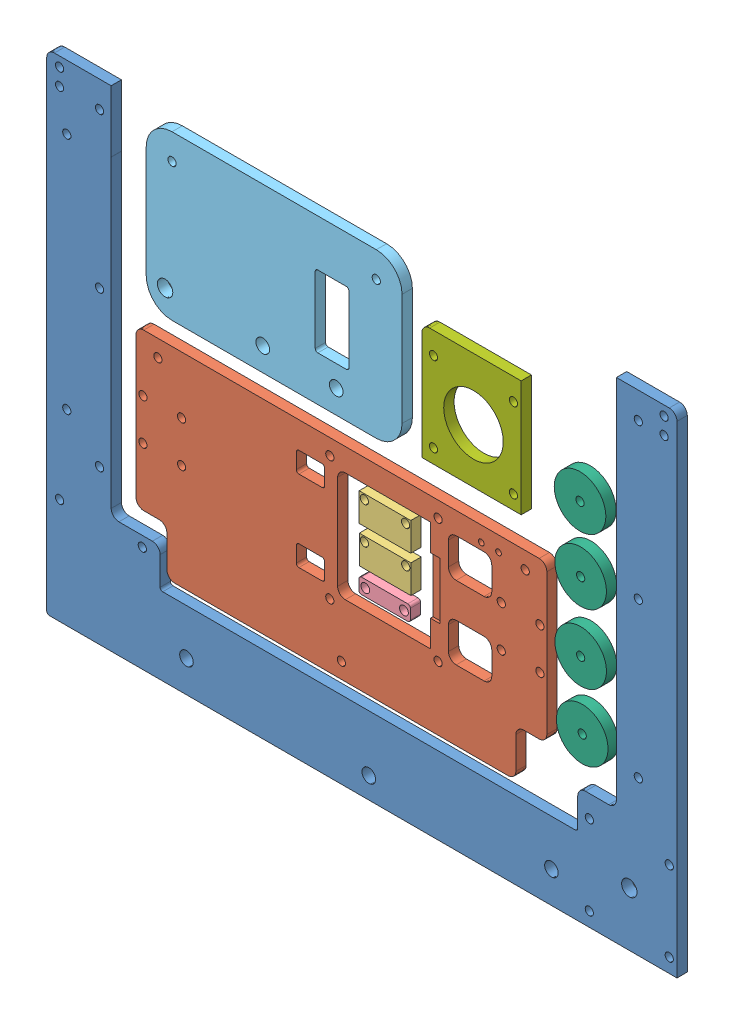
SolidWorks assembly Z AND Y FRAME PLUS SMALL ONES3, configuration Default. Lengths in mm.
Overall size (255.5 200 4).
11 component instances, 7 part files, 18 mates.
Components (placement in the parent):
- Z Frame-2: Z Frame [Valor predeterminado] at (-101.1725 37.5207 0) size (250 190 4)
- Bed Support2-3: Bed Support2 [Default] at (31.4027 -73.1228 4) x (-1 0 0) z (0 0 -1) size (159.38 135.83 4)
- BELT HOLDER-3: BELT HOLDER [Default] at (-20.0811 -6.5358 4) x (-1 0 0) z (0 0 -1) size (20.01 11 4)
- BELT HOLDER-4: BELT HOLDER [Default] at (-20.0363 -20.7491 4) x (-1 0 0) z (0 0 -1) size (20.01 11 4)
- Hotend bracket-3: Hotend bracket [Valor predeterminado] at (-72.0957 -68.0472 137.3657) x (-1 0 0) z (0 0 -1) size (19.93 5.9 4)
- Small foot2-3: Small foot2 [Default] at (223.7937 -22.704 0) x (0 -1 0) z (0 0 1) size (63.38 99.24 4)
- foot-1: foot [Default] at (-72.662 -313.517 0) x (-1 0 0) z (0 0 1) size (20 20 4)
- foot-2: foot [Default] at (123.6711 265.2856 0) size (20 20 4)
- foot-3: foot [Default] at (123.6648 292.063 0) size (20 20 4)
- foot-4: foot [Default] at (123.4165 317.2045 0) size (20 20 4)
- motor spacer-1: motor spacer [Default] at (-60.4449 125.3732 0) size (38.5 45 4)
Mates (geometry in assembly coordinates):
- Coincident6: coincident anti-aligned: plane of Z Frame-2 through (-178.9289 86.4051 0) normal (0 0 -1); plane of assembly through (0 0 0) normal (0 0 1)
- Coincident7: coincident: plane of Z Frame-2 through (62.5711 -100.5949 4) normal (1 0 0); line of assembly
- Coincident8: coincident: plane of Z Frame-2 through (67.0711 -100.5949 4) normal (0 -1 0); line of assembly
- Coincident9: coincident aligned: plane of Z Frame-2 through (-178.9289 86.4051 4) normal (0 0 1); plane of Bed Support2-3 through (31.4027 -73.1228 4) normal (0 0 1)
- Coincident10: coincident aligned: plane of Bed Support2-3 through (31.4027 -73.1228 0) normal (0 0 -1); plane of BELT HOLDER-3 through (-20.0811 -6.5358 0) normal (0 0 -1)
- Coincident11: coincident aligned: plane of Z Frame-2 through (-178.9289 86.4051 4) normal (0 0 1); plane of Small foot2-3 through (223.7937 -22.704 4) normal (0 0 1)
- Parallel2: parallel anti-aligned: plane of Z Frame-2 through (-136.9289 -70.5949 4) normal (0 1 0); plane of Small foot2-3 through (-44.0757 22.3754 4) normal (0 -1 0)
- Coincident16: coincident aligned: plane of Z Frame-2 through (-178.9289 86.4051 4) normal (0 0 1); plane of foot-1 through (25.8016 -37.0118 4) normal (0 0 1)
- Coincident17: coincident aligned: plane of Z Frame-2 through (-178.9289 86.4051 4) normal (0 0 1); plane of motor spacer-1 through (-33.3739 66.7783 4) normal (0 0 1)
- Coincident19: coincident aligned: plane of Bed Support2-3 through (31.4027 -73.1228 0) normal (0 0 -1); plane of Hotend bracket-3 through (-72.0957 -68.0472 0) normal (0 0 -1)
- Coincident20: coincident aligned: plane of Bed Support2-3 through (31.4027 -73.1228 0) normal (0 0 -1); plane of BELT HOLDER-4 through (-20.0363 -20.7491 0) normal (0 0 -1)
- Coincident21: coincident aligned: plane of Z Frame-2 through (-178.9289 86.4051 0) normal (0 0 -1); plane of foot-2 through (25.2075 -11.2195 0) normal (0 0 -1)
- Coincident22: coincident aligned: plane of Z Frame-2 through (-178.9289 86.4051 0) normal (0 0 -1); plane of foot-3 through (25.2012 15.5578 0) normal (0 0 -1)
- Coincident23: coincident aligned: plane of Z Frame-2 through (-178.9289 86.4051 0) normal (0 0 -1); plane of foot-4 through (24.9529 40.6994 0) normal (0 0 -1)
- Parallel3: parallel: line of Z Frame-2 through (-136.9289 -70.5949 4) axis (1 0 0); plane of Bed Support2-3 through (0.0919 -65.3857 0) normal (0 -1 0)
- Parallel4: parallel: line of Bed Support2-3 through (-66.0986 -37.8425 4) axis (1 0 0); plane of Hotend bracket-3 through (-40.8736 -33.0074 0) normal (0 -1 0)
- Parallel5: parallel anti-aligned: line of Bed Support2-3 through (-66.0986 -37.8425 4) axis (1 0 0); line of BELT HOLDER-4 through (-40.6549 -23.7491 4) axis (-1 0 0)
- Parallel6: parallel anti-aligned: line of Bed Support2-3 through (-66.0986 -37.8425 4) axis (1 0 0); line of BELT HOLDER-3 through (-40.6996 -9.5358 4) axis (-1 0 0)
